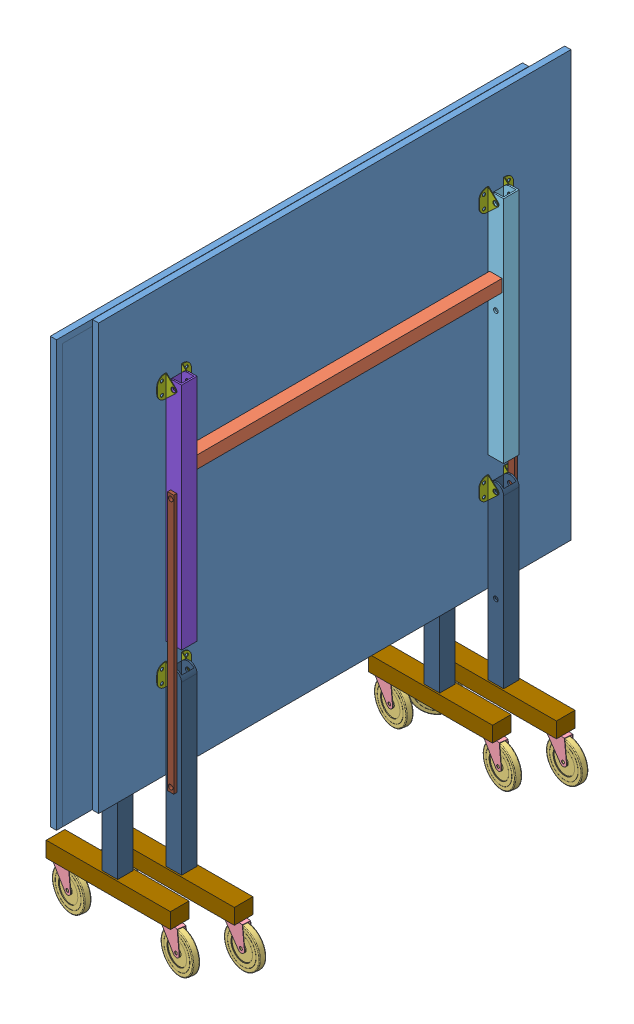
SolidWorks assembly assembly, configuration Default. Lengths in mm.
Overall size (581.84 1820.74 1639.85).
52 component instances, 11 part files, 133 mates.
Components (placement in the parent):
- Copy of tabletop^assembly-1: Copy of tabletop^assembly [Default] at (-385.0848 654.9756 586.0306) x (0 -1 0) z (0.001354 0 0.999999) size (1370 20.1 1525) (virtual)
- leg1-1: leg1 [Default] at (-410.7616 837.4756 86.0649) x (0.999999 0 -0.001354) z (0 -1 0) size (40 1000 40)
- Copy of tabletop^assembly-2: Copy of tabletop^assembly [Default] at (-343.9541 654.9756 471.1751) x (0 -1 0) z (-0.001354 0 -0.999999) size (1370 20.1 1525) (virtual)
- wheel-1: wheel [Default] at (-112.2639 -405.0239 -46.4747) x (-0.080628 0 0.996744) z (-0.996736 -0.004014 -0.080627) size (22.5 125 125)
- wheel support sheet-1: wheel support sheet [Default] at (-155.7324 -312.7529 -50.0409) x (-0.996744 0 -0.080628) z (0.080628 0 -0.996744) size (82.5 81.34 25)
- wheel support sheet-5: wheel support sheet [Default] at (-482.1484 -312.7529 990.8382) x (0.998595 0 -0.052996) z (0.052996 0 0.998595) size (82.5 81.34 25)
- wheel-3: wheel [Default] at (-525.7043 -405.0239 993.0999) x (-0.052996 0 -0.998595) z (0.129125 0.991605 -0.006853) size (22.5 125 125)
- wheel-4: wheel [Default] at (-110.8561 -405.0239 993.5244) x (-0.080628 0 0.996744) z (-0.996683 0.011046 -0.080623) size (22.5 125 125)
- wheel-5: wheel [Default] at (-520.656 -405.0239 -29.1191) x (-0.600076 0 -0.799943) z (0.796376 0.094331 -0.5974) size (22.5 125 125)
- wheel support sheet-6: wheel support sheet [Default] at (-485.7369 -312.7529 -55.2512) x (0.799943 0 -0.600076) z (0.600076 0 0.799943) size (82.5 81.34 25)
- wheel support sheet-7: wheel support sheet [Default] at (-154.3246 -312.7529 989.9582) x (-0.996744 0 -0.080628) z (0.080628 0 -0.996744) size (82.5 81.34 25)
- Copy of leg^assembly-5: Copy of leg^assembly [Default] at (-409.3809 342.4756 1106.064) x (-0.999999 0 0.001354) z (-0.001354 0 -0.999999) size (50 740 50) (virtual)
- Copy of Copy of leg^assembly-6: Copy of Copy of leg^assembly [Default] at (-410.7887 342.4756 66.0649) x (0.999999 0 -0.001354) z (0.001354 0 0.999999) size (50 740 50) (virtual)
- leg hinge-1: leg hinge [Default] at (-384.4147 1040.964 1081.0302) x (-0.001354 0 -0.999999) z (0 1 0) size (30 39.7 70)
- leg hinge-2: leg hinge [Default] at (-385.7548 1073.9872 91.0311) x (0.001354 0 0.999999) z (0 -1 0) size (30 39.7 70)
- leg hinge-3: leg hinge [Default] at (-385.8225 1040.964 41.0311) x (-0.001354 0 -0.999999) z (0 1 0) size (30 39.7 70)
- leg hinge-5: leg hinge [Default] at (-384.3471 1073.9872 1131.0301) x (0.001354 0 0.999999) z (0 -1 0) size (30 39.7 70)
- leg hinge-6: leg hinge [Default] at (-343.2164 1040.964 1016.1746) x (0.001354 0 0.999999) z (0 1 0) size (30 39.7 70)
- leg hinge-7: leg hinge [Default] at (-344.6919 1073.9872 -73.8244) x (-0.001354 0 -0.999999) z (0 -1 0) size (30 39.7 70)
- leg hinge-8: leg hinge [Default] at (-344.6242 1040.964 -23.8245) x (0.001354 0 0.999999) z (0 1 0) size (30 39.7 70)
- leg hinge-9: leg hinge [Default] at (-343.2841 1073.9872 966.1746) x (-0.001354 0 -0.999999) z (0 -1 0) size (30 39.7 70)
- leg1-5: leg1 [Default] at (-319.6309 837.4756 -28.8583) x (0.999999 0 -0.001354) z (0 -1 0) size (40 1000 40)
- Copy of leg^assembly-7: Copy of leg^assembly [Default] at (-319.6578 342.4756 -48.8583) x (0.999999 0 -0.001354) z (0.001354 0 0.999999) size (50 740 50) (virtual)
- Copy (2) of Copy of Copy of leg^assembly-8: Copy (2) of Copy of Copy of leg^assembly [Default] at (-318.25 342.4756 991.1407) x (-0.999999 0 0.001354) z (-0.001354 0 -0.999999) size (50 740 50) (virtual)
- Copy (2) of Copy of leg^assembly-8: Copy (2) of Copy of leg^assembly [Default] at (-118.2503 -311.1814 990.87) x (-0.001354 0 -0.999999) z (0 1 0) size (60 400 50) (virtual)
- Copy (2) of Copy of leg^assembly-9: Copy (2) of Copy of leg^assembly [Default] at (-519.6577 -311.1814 -48.5876) x (0.001354 0 0.999999) z (0 1 0) size (60 400 50) (virtual)
- Copy of Copy of Copy of leg^assembly-9: Copy of Copy of Copy of leg^assembly [Default] at (-318.2501 -291.1814 991.1407) x (0.999999 0 -0.001354) z (0.001354 0 0.999999) size (50 568.66 50) (virtual)
- Copy of Copy of Copy of leg^assembly-11: Copy of Copy of Copy of leg^assembly [Default] at (-319.6579 -291.1814 -48.8583) x (0.999999 0 -0.001354) z (0.001354 0 0.999999) size (50 568.66 50) (virtual)
- leg hinge-11: leg hinge [Default] at (-344.6917 268.9872 -73.8245) x (-0.001354 0 -0.999999) z (0 -1 0) size (30 39.7 70)
- leg hinge-12: leg hinge [Default] at (-343.2839 268.9872 966.1746) x (-0.001354 0 -0.999999) z (0 -1 0) size (30 39.7 70)
- leg hinge-13: leg hinge [Default] at (-343.2162 235.964 1016.1746) x (0.001354 0 0.999999) z (0 1 0) size (30 39.7 70)
- leg hinge-14: leg hinge [Default] at (-344.624 235.964 -23.8245) x (0.001354 0 0.999999) z (0 1 0) size (30 39.7 70)
- bridge-1: bridge [Default] at (-318.3896 354.9756 -73.8601) x (0 1 0) z (-0.999999 0 0.001354) size (835 10 20)
- bridge-2: bridge [Default] at (-316.9006 354.9756 1026.1389) x (0 1 0) z (-0.999999 0 0.001354) size (835 10 20)
- leg hinge-18: leg hinge [Default] at (-384.4147 235.964 1081.0302) x (-0.001354 0 -0.999999) z (0 1 0) size (30 39.7 70)
- leg hinge-19: leg hinge [Default] at (-385.8225 235.964 41.0311) x (-0.001354 0 -0.999999) z (0 1 0) size (30 39.7 70)
- leg hinge-20: leg hinge [Default] at (-385.7548 268.9872 91.0311) x (0.001354 0 0.999999) z (0 -1 0) size (30 39.7 70)
- leg hinge-21: leg hinge [Default] at (-384.3471 268.9872 1131.0301) x (0.001354 0 0.999999) z (0 -1 0) size (30 39.7 70)
- Copy of Copy of Copy of leg^assembly-13: Copy of Copy of Copy of leg^assembly [Default] at (-409.3809 -291.1814 1106.064) x (0.999999 0 -0.001354) z (0.001354 0 0.999999) size (50 568.66 50) (virtual)
- Copy of Copy of Copy of leg^assembly-14: Copy of Copy of Copy of leg^assembly [Default] at (-410.7887 -291.1814 66.0649) x (0.999999 0 -0.001354) z (0.001354 0 0.999999) size (50 568.66 50) (virtual)
- Copy (2) of Copy of leg^assembly-14: Copy (2) of Copy of leg^assembly [Default] at (-609.3807 -311.1814 1106.3347) x (0.001354 0 0.999999) z (0 1 0) size (60 400 50) (virtual)
- Copy (2) of Copy of leg^assembly-15: Copy (2) of Copy of leg^assembly [Default] at (-610.7885 -311.1814 66.3357) x (0.001354 0 0.999999) z (0 1 0) size (60 400 50) (virtual)
- wheel support sheet-10: wheel support sheet [Default] at (-245.3542 -312.7529 1104.059) x (-0.987968 0 -0.154656) z (0.154656 0 -0.987968) size (82.5 81.34 25)
- wheel-9: wheel [Default] at (-202.2721 -405.0239 1110.8535) x (-0.154656 0 0.987968) z (-0.034164 0.999402 -0.005348) size (22.5 125 125)
- wheel support sheet-11: wheel support sheet [Default] at (-595.3538 -312.7529 1104.5328) x (-0.987968 0 -0.154656) z (0.154656 0 -0.987968) size (82.5 81.34 25)
- wheel support sheet-12: wheel support sheet [Default] at (-596.7616 -312.7529 64.5338) x (-0.987968 0 -0.154656) z (0.154656 0 -0.987968) size (82.5 81.34 25)
- wheel support sheet-13: wheel support sheet [Default] at (-246.7589 -312.7529 64.0414) x (-0.987705 0 -0.15633) z (0.15633 0 -0.987705) size (82.5 81.34 25)
- wheel-10: wheel [Default] at (-203.6884 -405.0239 70.9089) x (-0.15633 0 0.987705) z (-0.958469 -0.241504 -0.151702) size (22.5 125 125)
- wheel-11: wheel [Default] at (-553.6795 -405.0239 71.328) x (0.154656 0 -0.987968) z (0.983989 0.089667 0.154033) size (22.5 125 125)
- wheel-12: wheel [Default] at (-552.2717 -405.0239 1111.3271) x (0.154656 0 -0.987968) z (0.237909 -0.970573 0.037242) size (22.5 125 125)
- bridge-3: bridge [Default] at (-409.5338 354.9756 31.0632) x (0 -1 0) z (-0.999999 0 0.001354) size (835 10 20)
- bridge-4: bridge [Default] at (-408.0448 354.9756 1131.0622) x (0 -1 0) z (-0.999999 0 0.001354) size (835 10 20)
Mates (geometry in assembly coordinates):
- Concentric1: concentric anti-aligned: cylinder of wheel-1 through (-111.3568 -405.0239 -57.6882) axis (-0.080628 0 0.996744) radius 5; cylinder of wheel support sheet-1 through (-111.3568 -405.0239 -57.6882) axis (0.080628 0 -0.996744) radius 5
- Coincident4: coincident anti-aligned: plane of wheel-1 through (-111.3568 -405.0239 -57.6882) normal (0.080628 0 -0.996744); plane of wheel support sheet-1 through (-111.3568 -405.0239 -57.6882) normal (-0.080628 0 0.996744)
- Coincident5: coincident anti-aligned: plane of wheel-5 through (-513.905 -405.0239 -20.1196) normal (0.600076 0 0.799943); plane of wheel support sheet-6 through (-513.905 -405.0239 -20.1196) normal (-0.600076 0 -0.799943)
- Concentric2: concentric anti-aligned: cylinder of wheel-5 through (-513.905 -405.0239 -20.1196) axis (-0.600076 0 -0.799943) radius 5; cylinder of wheel support sheet-6 through (-513.905 -405.0239 -20.1196) axis (0.600076 0 0.799943) radius 5
- Coincident7: coincident anti-aligned: circle of wheel support sheet-5; cylinder of wheel-3 through (-525.1081 -405.0239 1004.3342) axis (-0.052996 0 -0.998595) radius 5
- Coincident8: coincident anti-aligned: plane of wheel support sheet-5 through (-526.3005 -405.0239 981.8658) normal (0.052996 0 0.998595); plane of wheel-3 through (-526.3005 -405.0239 981.8658) normal (-0.052996 0 -0.998595)
- Coincident9: coincident anti-aligned: plane of wheel-4 through (-109.949 -405.0239 982.3109) normal (0.080628 0 -0.996744); plane of wheel support sheet-7 through (-109.949 -405.0239 982.3109) normal (-0.080628 0 0.996744)
- Concentric3: concentric aligned: cylinder of wheel-4 through (-109.949 -405.0239 982.3109) axis (-0.080628 0 0.996744) radius 5; cylinder of wheel support sheet-7 through (-111.7632 -405.0239 1004.7376) axis (-0.080628 0 0.996744) radius 5
- Coincident13: coincident aligned: plane of wheel support sheet-5 through (-530.0348 -336.1814 1005.8474) normal (0 1 0); plane of wheel support sheet-7 through (-104.8645 -336.1814 981.4681) normal (0 1 0)
- Coincident20: coincident anti-aligned: plane of leg1-1 through (-1234.4072 52.4756 1087.1807) normal (0 1 0); plane of Copy of Copy of leg^assembly-6 through (-1235.8217 52.4756 42.1807) normal (0 -1 0)
- Coincident21: coincident anti-aligned: plane of leg1-1 through (-1234.4072 52.4756 1087.1807) normal (-0.999999 0 0.001354); plane of Copy of Copy of leg^assembly-6 through (-1235.815 277.4756 47.1817) normal (0.999999 0 -0.001354)
- Coincident22: coincident aligned: plane of leg1-1 through (-1235.7608 12.4756 87.1817) normal (-0.001354 0 -0.999999); plane of Copy of Copy of leg^assembly-6 through (-1235.7608 277.4756 87.1817) normal (-0.001354 0 -0.999999)
- Coincident23: coincident anti-aligned: plane of leg1-1 through (-1194.4072 52.4756 1087.1266) normal (0.999999 0 -0.001354); plane of Copy of leg^assembly-5 through (-1194.3531 277.4756 1127.1266) normal (-0.999999 0 0.001354)
- Coincident24: coincident anti-aligned: plane of leg1-1 through (-1234.4072 12.4756 1087.1807) normal (0 -1 0); plane of Copy of leg^assembly-5 through (-1194.3463 12.4756 1132.1276) normal (0 1 0)
- Coincident25: coincident aligned: plane of leg1-1 through (-1234.4072 12.4756 1087.1807) normal (0.001354 0 0.999999); plane of Copy of leg^assembly-5 through (-1194.4072 277.4756 1087.1266) normal (0.001354 0 0.999999)
- Concentric4: concentric aligned: cylinder of Copy of leg^assembly-5 through (-1214.414 252.4756 1082.1537) axis (0.001354 0 0.999999) radius 7.5; cylinder of leg hinge-1 through (-1214.4167 252.4756 1080.1537) axis (0.001354 0 0.999999) radius 7.5
- Coincident26: coincident anti-aligned: plane of Copy of tabletop^assembly-1; plane of leg hinge-1
- Coincident35: coincident anti-aligned: plane of Copy of tabletop^assembly-1; plane of leg hinge-3
- Coincident36: coincident anti-aligned: plane of Copy of Copy of leg^assembly-6 through (-1240.8217 277.4756 42.1885) normal (-0.001354 0 -0.999999); plane of leg hinge-3 through (-1180.8218 275.4756 42.1072) normal (0.001354 0 0.999999)
- Concentric5: concentric anti-aligned: cylinder of Copy of Copy of leg^assembly-6 through (-1215.7541 252.4756 92.1546) axis (-0.001354 0 -0.999999) radius 7.5; cylinder of leg hinge-3 through (-1215.8245 252.4756 40.1546) axis (0.001354 0 0.999999) radius 7.5
- Coincident37: coincident anti-aligned: plane of Copy of Copy of leg^assembly-6 through (-1240.7541 277.4756 92.1884) normal (0.001354 0 0.999999); plane of leg hinge-2 through (-1250.7541 275.4756 92.202) normal (-0.001354 0 -0.999999)
- Coincident38: coincident anti-aligned: plane of Copy of tabletop^assembly-1; plane of leg hinge-2
- Coincident39: coincident aligned: circle of Copy of Copy of leg^assembly-6; cylinder of leg hinge-2 through (-1215.7514 252.4756 94.1546) axis (-0.001354 0 -0.999999) radius 7.5
- Coincident43: coincident anti-aligned: plane of Copy of leg^assembly-5 through (-1189.414 277.4756 1082.1198) normal (-0.001354 0 -0.999999); plane of leg hinge-1 through (-1179.414 275.4756 1082.1063) normal (0.001354 0 0.999999)
- Coincident44: coincident anti-aligned: plane of Copy of leg^assembly-5 through (-1189.3463 277.4756 1132.1198) normal (0.001354 0 0.999999); plane of leg hinge-5 through (-1249.3463 275.4756 1132.201) normal (-0.001354 0 -0.999999)
- Coincident45: coincident anti-aligned: plane of Copy of tabletop^assembly-1; plane of leg hinge-5
- Concentric6: concentric anti-aligned: cylinder of Copy of leg^assembly-5 through (-1214.414 252.4756 1082.1537) axis (0.001354 0 0.999999) radius 7.5; cylinder of leg hinge-5 through (-1214.3436 252.4756 1134.1536) axis (-0.001354 0 -0.999999) radius 7.5
- Concentric7: concentric anti-aligned: cylinder of Copy of tabletop^assembly-1 through (-1234.326 287.4756 1147.1807) axis (0 -1 0) radius 5; cylinder of leg hinge-5 through (-1234.326 275.4756 1147.1807) axis (0 1 0) radius 5
- Concentric8: concentric anti-aligned: cylinder of Copy of tabletop^assembly-2 through (506.8033 287.4756 1030.0239) axis (0 -1 0) radius 5; cylinder of leg hinge-6 through (506.8033 275.4756 1030.0239) axis (0 1 0) radius 5
- Coincident52: coincident anti-aligned: plane of Copy of tabletop^assembly-2; plane of leg hinge-6
- Concentric9: concentric anti-aligned: cylinder of Copy of tabletop^assembly-2 through (466.8033 287.4756 1030.0781) axis (0 -1 0) radius 5; cylinder of leg hinge-6 through (466.8033 275.4756 1030.0781) axis (0 1 0) radius 5
- Coincident56: coincident aligned: plane of leg hinge-7 through (450.3076 277.4756 -74.9006) normal (0 1 0); plane of leg hinge-8 through (520.3752 277.4756 -24.9954) normal (0 1 0)
- Coincident57: coincident aligned: plane of leg hinge-7 through (450.3076 277.4756 -74.9006) normal (0 1 0); plane of leg hinge-9 through (451.7153 277.4756 965.0985) normal (0 1 0)
- Coincident58: coincident anti-aligned: plane of Copy of tabletop^assembly-2; plane of leg hinge-9
- Concentric10: concentric anti-aligned: cylinder of Copy of tabletop^assembly-2 through (466.695 287.4756 950.0782) axis (0 -1 0) radius 5; cylinder of leg hinge-9 through (466.695 275.4756 950.0782) axis (0 1 0) radius 5
- Concentric11: concentric anti-aligned: cylinder of Copy of tabletop^assembly-2 through (506.695 287.4756 950.024) axis (0 -1 0) radius 5; cylinder of leg hinge-9 through (506.695 275.4756 950.024) axis (0 1 0) radius 5
- Concentric12: concentric anti-aligned: cylinder of Copy of tabletop^assembly-2 through (505.2872 287.4756 -89.975) axis (0 -1 0) radius 5; cylinder of leg hinge-7 through (505.2872 275.4756 -89.975) axis (0 1 0) radius 5
- Concentric13: concentric anti-aligned: cylinder of Copy of tabletop^assembly-2 through (465.2872 287.4756 -89.9209) axis (0 -1 0) radius 5; cylinder of leg hinge-7 through (465.2872 275.4756 -89.9209) axis (0 1 0) radius 5
- Concentric14: concentric anti-aligned: cylinder of Copy of tabletop^assembly-2 through (465.3955 287.4756 -9.921) axis (0 -1 0) radius 5; cylinder of leg hinge-8 through (465.3955 275.4756 -9.921) axis (0 1 0) radius 5
- Coincident60: coincident aligned: cylinder of Copy of tabletop^assembly-2 through (-354.604 1077.4756 -8.811) axis (0.999999 0 -0.001354) radius 5; circle of leg hinge-8
- Coincident61: coincident anti-aligned: plane of leg hinge-8 through (450.3752 275.4756 -24.9006) normal (-0.001354 0 -0.999999); plane of Copy of leg^assembly-7 through (460.3752 277.4756 -24.9142) normal (0.001354 0 0.999999)
- Coincident63: coincident anti-aligned: plane of leg hinge-7 through (520.3075 275.4756 -74.9953) normal (0.001354 0 0.999999); plane of Copy of leg^assembly-7 through (460.3076 277.4756 -74.9141) normal (-0.001354 0 -0.999999)
- Concentric15: concentric aligned: cylinder of leg hinge-8 through (485.3779 252.4756 -22.948) axis (-0.001354 0 -0.999999) radius 7.5; cylinder of Copy of leg^assembly-7 through (485.3752 252.4756 -24.948) axis (-0.001354 0 -0.999999) radius 7.5
- Coincident72: coincident anti-aligned: plane of leg1-5 through (506.7221 52.4756 970.024) normal (0.999999 0 -0.001354); plane of Copy of leg^assembly-7 through (505.3143 277.4756 -69.975) normal (-0.999999 0 0.001354)
- Concentric16: concentric anti-aligned: cylinder of leg hinge-6 through (486.7857 252.4756 1017.051) axis (-0.001354 0 -0.999999) radius 7.5; cylinder of Copy (2) of Copy of Copy of leg^assembly-8 through (486.7153 252.4756 965.0511) axis (0.001354 0 0.999999) radius 7.5
- Coincident73: coincident anti-aligned: plane of leg hinge-6 through (451.783 275.4756 1015.0984) normal (-0.001354 0 -0.999999); plane of Copy (2) of Copy of Copy of leg^assembly-8 through (511.783 277.4756 1015.0172) normal (0.001354 0 0.999999)
- Coincident74: coincident anti-aligned: plane of leg1-5 through (466.7221 52.4756 970.0781) normal (-0.999999 0 0.001354); plane of Copy (2) of Copy of Copy of leg^assembly-8 through (466.7762 277.4756 1010.0781) normal (0.999999 0 -0.001354)
- Coincident75: coincident anti-aligned: plane of leg1-5 through (466.7221 52.4756 970.0781) normal (0 1 0); plane of Copy (2) of Copy of Copy of leg^assembly-8 through (506.783 52.4756 1015.025) normal (0 -1 0)
- Coincident77: coincident aligned: plane of leg1-5 through (465.3685 12.4756 -29.9209) normal (-0.001354 0 -0.999999); plane of Copy of leg^assembly-7 through (465.3685 277.4756 -29.9209) normal (-0.001354 0 -0.999999)
- LimitDistance15: limit distance = 50 mm: line of Copy (2) of Copy of Copy of leg^assembly-8 through (-293.2165 1082.4756 1016.1069) axis (-0.001354 0 -0.999999); plane of Copy of tabletop^assembly-2 through (-344.9863 1339.9756 -291.3243) normal (0.999999 0 -0.001354)
- Concentric17: concentric aligned: cylinder of wheel support sheet-7 through (-143.2503 -336.1814 990.9038) axis (0 -1 0) radius 5; cylinder of Copy (2) of Copy of leg^assembly-8 through (-143.2503 -286.1804 990.9038) axis (0 -1 0) radius 7.5
- Coincident80: coincident anti-aligned: plane of wheel support sheet-7 through (-104.8645 -336.1814 981.4681) normal (0 1 0); plane of Copy (2) of Copy of leg^assembly-8 through (-518.2093 -336.1814 1021.4114) normal (0 -1 0)
- Concentric18: concentric aligned: cylinder of wheel support sheet-5 through (-493.25 -336.1814 991.3776) axis (0 -1 0) radius 5; cylinder of Copy (2) of Copy of leg^assembly-8 through (-493.25 -286.1804 991.3776) axis (0 -1 0) radius 7.5
- Coincident81: coincident anti-aligned: plane of wheel support sheet-6 through (-517.1546 -336.1814 -16.1193) normal (0 1 0); plane of Copy (2) of Copy of leg^assembly-9 through (-119.6987 -336.1814 -79.129) normal (0 -1 0)
- Coincident82: coincident anti-aligned: plane of wheel support sheet-1 through (-106.2723 -336.1814 -58.531) normal (0 1 0); plane of Copy (2) of Copy of leg^assembly-9 through (-119.6987 -336.1814 -79.129) normal (0 -1 0)
- Concentric19: concentric aligned: cylinder of wheel support sheet-6 through (-494.6577 -336.1814 -48.6214) axis (0 -1 0) radius 5; cylinder of Copy (2) of Copy of leg^assembly-9 through (-494.6577 -286.1804 -48.6214) axis (0 -1 0) radius 7.5
- Concentric20: concentric aligned: cylinder of wheel support sheet-1 through (-144.6581 -336.1814 -49.0952) axis (0 -1 0) radius 5; cylinder of Copy (2) of Copy of leg^assembly-9 through (-144.6581 -286.1804 -49.0952) axis (0 -1 0) radius 7.5
- Coincident84: coincident anti-aligned: plane of Copy (2) of Copy of leg^assembly-8 through (-343.2839 -336.1824 966.1746) normal (0.999999 0 -0.001354); plane of Copy of Copy of Copy of leg^assembly-9 through (-343.2839 277.4756 966.1746) normal (-0.999999 0 0.001354)
- Coincident85: coincident aligned: plane of Copy (2) of Copy of leg^assembly-8 through (-518.2161 -291.1814 1016.4114) normal (0 -1 0); plane of Copy of Copy of Copy of leg^assembly-9 through (-293.284 -291.1814 966.1069) normal (0 -1 0)
- Coincident86: coincident anti-aligned: plane of Copy (2) of Copy of leg^assembly-8 through (-518.2838 -331.1814 966.4115) normal (0.001354 0 0.999999); plane of Copy of Copy of Copy of leg^assembly-9 through (-343.2839 277.4756 966.1746) normal (-0.001354 0 -0.999999)
- Coincident87: coincident anti-aligned: plane of Copy (2) of Copy of leg^assembly-9 through (-119.6919 -331.1814 -74.129) normal (0.001354 0 0.999999); plane of Copy of Copy of Copy of leg^assembly-11 through (-344.6917 277.4756 -73.8245) normal (-0.001354 0 -0.999999)
- Coincident88: coincident: line of Copy (2) of Copy of leg^assembly-9 through (-344.6917 -291.1814 -73.8245) axis (0.001354 0 0.999999); plane of Copy of Copy of Copy of leg^assembly-11 through (-344.6917 277.4756 -73.8245) normal (-0.999999 0 0.001354)
- Coincident89: coincident aligned: plane of Copy (2) of Copy of leg^assembly-9 through (-119.6919 -291.1814 -74.129) normal (0 -1 0); plane of Copy of Copy of Copy of leg^assembly-11 through (-294.6918 -291.1814 -73.8921) normal (0 -1 0)
- Concentric22: concentric anti-aligned: cylinder of Copy of tabletop^assembly-2 through (-299.7121 287.4756 -88.8853) axis (0 -1 0) radius 5; cylinder of leg hinge-11 through (-299.7121 275.4756 -88.8853) axis (0 1 0) radius 5
- Concentric23: concentric anti-aligned: cylinder of Copy of tabletop^assembly-2 through (-339.712 287.4756 -88.8312) axis (0 -1 0) radius 5; cylinder of leg hinge-11 through (-339.712 275.4756 -88.8312) axis (0 1 0) radius 5
- Coincident92: coincident anti-aligned: plane of Copy of tabletop^assembly-2; plane of leg hinge-11
- Concentric26: concentric anti-aligned: cylinder of Copy of tabletop^assembly-2 through (-299.6038 287.4756 -8.8854) axis (0 -1 0) radius 5; cylinder of leg hinge-14 through (-299.6038 275.4756 -8.8854) axis (0 1 0) radius 5
- Concentric27: concentric anti-aligned: cylinder of Copy of tabletop^assembly-2 through (-339.6037 287.4756 -8.8313) axis (0 -1 0) radius 5; cylinder of leg hinge-14 through (-339.6037 275.4756 -8.8313) axis (0 1 0) radius 5
- Coincident95: coincident anti-aligned: plane of Copy of tabletop^assembly-2; plane of leg hinge-14
- Coincident96: coincident anti-aligned: plane of Copy of Copy of Copy of leg^assembly-11 through (-344.6917 277.4756 -73.8245) normal (-0.001354 0 -0.999999); plane of leg hinge-11 through (-284.6918 275.4756 -73.9057) normal (0.001354 0 0.999999)
- Concentric28: concentric anti-aligned: cylinder of Copy of Copy of Copy of leg^assembly-11 through (-319.6241 252.4756 -23.8583) axis (-0.001354 0 -0.999999) radius 7.5; cylinder of leg hinge-11 through (-319.6944 252.4756 -75.8583) axis (0.001354 0 0.999999) radius 7.5
- Coincident100: coincident anti-aligned: plane of Copy of tabletop^assembly-2; plane of leg hinge-13
- Coincident101: coincident anti-aligned: plane of Copy of tabletop^assembly-2; plane of leg hinge-12
- Concentric29: concentric anti-aligned: cylinder of Copy of tabletop^assembly-2 through (-338.1959 287.4756 1031.1678) axis (0 -1 0) radius 5; cylinder of leg hinge-13 through (-338.1959 275.4756 1031.1678) axis (0 1 0) radius 5
- Concentric30: concentric anti-aligned: cylinder of Copy of tabletop^assembly-2 through (-298.196 287.4756 1031.1136) axis (0 -1 0) radius 5; cylinder of leg hinge-13 through (-298.196 275.4756 1031.1136) axis (0 1 0) radius 5
- Concentric31: concentric anti-aligned: cylinder of Copy of tabletop^assembly-2 through (-298.3043 287.4756 951.1137) axis (0 -1 0) radius 5; cylinder of leg hinge-12 through (-298.3043 275.4756 951.1137) axis (0 1 0) radius 5
- Concentric32: concentric anti-aligned: cylinder of Copy of tabletop^assembly-2 through (-338.3042 287.4756 951.1678) axis (0 -1 0) radius 5; cylinder of leg hinge-12 through (-338.3042 275.4756 951.1678) axis (0 1 0) radius 5
- Coincident102: coincident anti-aligned: plane of Copy of Copy of Copy of leg^assembly-9 through (-343.2162 277.4756 1016.1746) normal (0.001354 0 0.999999); plane of leg hinge-13 through (-353.2162 275.4756 1016.1881) normal (-0.001354 0 -0.999999)
- Concentric33: concentric aligned: cylinder of Copy of Copy of Copy of leg^assembly-9 through (-318.2163 252.4756 1016.1407) axis (-0.001354 0 -0.999999) radius 7.5; cylinder of leg hinge-13 through (-318.2136 252.4756 1018.1407) axis (-0.001354 0 -0.999999) radius 7.5
- Concentric34: concentric anti-aligned: cylinder of Copy of leg^assembly-7 through (485.3752 -47.5244 -24.948) axis (-0.001354 0 -0.999999) radius 7.5; cylinder of bridge-1 through (485.294 -47.5244 -84.948) axis (0.001354 0 0.999999) radius 7.5
- Coincident104: coincident anti-aligned: plane of Copy of leg^assembly-7 through (460.3076 277.4756 -74.9141) normal (-0.001354 0 -0.999999); plane of bridge-1 through (-334.6917 -37.5244 -73.838) normal (0.001354 0 0.999999)
- Concentric35: concentric anti-aligned: cylinder of Copy of Copy of Copy of leg^assembly-11 through (-319.6241 -47.5244 -23.8583) axis (-0.001354 0 -0.999999) radius 7.5; cylinder of bridge-1 through (-319.7053 -47.5244 -83.8583) axis (0.001354 0 0.999999) radius 7.5
- Coincident105: coincident anti-aligned: plane of Copy (2) of Copy of Copy of leg^assembly-8 through (511.783 277.4756 1015.0172) normal (0.001354 0 0.999999); plane of bridge-2 through (-333.2163 -37.5244 1016.161) normal (-0.001354 0 -0.999999)
- Concentric36: concentric aligned: cylinder of Copy (2) of Copy of Copy of leg^assembly-8 through (486.7153 -47.5244 965.0511) axis (0.001354 0 0.999999) radius 7.5; cylinder of bridge-2 through (486.783 -47.5244 1015.051) axis (0.001354 0 0.999999) radius 7.5
- Concentric37: concentric anti-aligned: cylinder of Copy of Copy of Copy of leg^assembly-9 through (-318.2163 -47.5244 1016.1407) axis (-0.001354 0 -0.999999) radius 7.5; cylinder of bridge-2 through (-318.2163 -47.5244 1016.1407) axis (0.001354 0 0.999999) radius 7.5
- Coincident110: coincident aligned: plane of leg hinge-19 through (-445.8225 277.4756 41.1123) normal (0 1 0); plane of leg hinge-20 through (-375.7549 277.4756 91.0175) normal (0 1 0)
- Coincident111: coincident aligned: plane of leg hinge-18 through (-444.4147 277.4756 1081.1114) normal (0 1 0); plane of leg hinge-20 through (-375.7549 277.4756 91.0175) normal (0 1 0)
- Coincident112: coincident aligned: plane of leg hinge-18 through (-444.4147 277.4756 1081.1114) normal (0 1 0); plane of leg hinge-21 through (-374.3471 277.4756 1131.0166) normal (0 1 0)
- Concentric38: concentric anti-aligned: cylinder of Copy of tabletop^assembly-1 through (-430.7345 287.4756 106.092) axis (0 -1 0) radius 5; cylinder of leg hinge-20 through (-430.7345 275.4756 106.092) axis (0 1 0) radius 5
- Concentric39: concentric anti-aligned: cylinder of Copy of tabletop^assembly-1 through (-390.7345 287.4756 106.0378) axis (0 -1 0) radius 5; cylinder of leg hinge-20 through (-390.7345 275.4756 106.0378) axis (0 1 0) radius 5
- Concentric40: concentric anti-aligned: cylinder of Copy of tabletop^assembly-1 through (-430.8428 287.4756 26.092) axis (0 -1 0) radius 5; cylinder of leg hinge-19 through (-430.8428 275.4756 26.092) axis (0 1 0) radius 5
- Concentric41: concentric anti-aligned: cylinder of Copy of tabletop^assembly-1 through (-390.8428 287.4756 26.0379) axis (0 -1 0) radius 5; cylinder of leg hinge-19 through (-390.8428 275.4756 26.0379) axis (0 1 0) radius 5
- Concentric42: concentric anti-aligned: cylinder of Copy of tabletop^assembly-1 through (-429.3267 287.4756 1146.091) axis (0 -1 0) radius 5; cylinder of leg hinge-21 through (-429.3267 275.4756 1146.091) axis (0 1 0) radius 5
- Concentric43: concentric anti-aligned: cylinder of Copy of tabletop^assembly-1 through (-389.3268 287.4756 1146.0369) axis (0 -1 0) radius 5; cylinder of leg hinge-21 through (-389.3268 275.4756 1146.0369) axis (0 1 0) radius 5
- Concentric44: concentric anti-aligned: cylinder of Copy of tabletop^assembly-1 through (-389.435 287.4756 1066.0369) axis (0 -1 0) radius 5; cylinder of leg hinge-18 through (-389.435 275.4756 1066.0369) axis (0 1 0) radius 5
- Concentric45: concentric anti-aligned: cylinder of Copy of tabletop^assembly-1 through (-429.435 287.4756 1066.0911) axis (0 -1 0) radius 5; cylinder of leg hinge-18 through (-429.435 275.4756 1066.0911) axis (0 1 0) radius 5
- Coincident113: coincident anti-aligned: plane of Copy of tabletop^assembly-1; plane of leg hinge-18
- Coincident115: coincident anti-aligned: plane of leg hinge-18 through (-374.4148 275.4756 1081.0166) normal (0.001354 0 0.999999); plane of Copy of Copy of Copy of leg^assembly-13 through (-434.4147 277.4756 1081.0978) normal (-0.001354 0 -0.999999)
- Concentric46: concentric aligned: cylinder of leg hinge-21 through (-409.3443 252.4756 1133.0639) axis (-0.001354 0 -0.999999) radius 7.5; cylinder of Copy of Copy of Copy of leg^assembly-13 through (-409.347 252.4756 1131.0639) axis (-0.001354 0 -0.999999) radius 7.5
- Coincident116: coincident anti-aligned: plane of leg hinge-20 through (-445.7548 275.4756 91.1123) normal (-0.001354 0 -0.999999); plane of Copy of Copy of Copy of leg^assembly-14 through (-435.7548 277.4756 91.0987) normal (0.001354 0 0.999999)
- Concentric47: concentric aligned: cylinder of leg hinge-20 through (-410.7521 252.4756 93.0649) axis (-0.001354 0 -0.999999) radius 7.5; cylinder of Copy of Copy of Copy of leg^assembly-14 through (-410.7548 252.4756 91.0649) axis (-0.001354 0 -0.999999) radius 7.5
- Coincident119: coincident anti-aligned: plane of Copy of Copy of Copy of leg^assembly-13 through (-434.347 277.4756 1131.0978) normal (0.001354 0 0.999999); plane of Copy (2) of Copy of leg^assembly-14 through (-209.3472 -331.1814 1130.7932) normal (-0.001354 0 -0.999999)
- Coincident120: coincident anti-aligned: plane of Copy of Copy of Copy of leg^assembly-13 through (-384.4147 277.4756 1081.0302) normal (0.999999 0 -0.001354); plane of Copy (2) of Copy of leg^assembly-14 through (-384.3471 -336.1824 1131.0301) normal (-0.999999 0 0.001354)
- Coincident121: coincident anti-aligned: plane of Copy of Copy of Copy of leg^assembly-14 through (-435.8225 277.4756 41.0988) normal (-0.001354 0 -0.999999); plane of Copy (2) of Copy of leg^assembly-15 through (-210.8227 -331.1814 40.7942) normal (0.001354 0 0.999999)
- Coincident122: coincident anti-aligned: plane of Copy of Copy of Copy of leg^assembly-14 through (-435.8225 277.4756 41.0988) normal (-0.999999 0 0.001354); plane of Copy (2) of Copy of leg^assembly-15 through (-435.7548 -336.1824 91.0987) normal (0.999999 0 -0.001354)
- Coincident124: coincident aligned: plane of Copy of Copy of Copy of leg^assembly-14 through (-385.8225 -291.1814 41.0311) normal (0 -1 0); plane of Copy (2) of Copy of leg^assembly-15 through (-210.8227 -291.1814 40.7942) normal (0 -1 0)
- Coincident125: coincident aligned: plane of Copy of Copy of Copy of leg^assembly-13 through (-384.4147 -291.1814 1081.0302) normal (0 -1 0); plane of Copy (2) of Copy of leg^assembly-14 through (-209.4149 -291.1814 1080.7933) normal (0 -1 0)
- Concentric48: concentric aligned: cylinder of Copy (2) of Copy of leg^assembly-14 through (-234.381 -286.1804 1105.8271) axis (0 -1 0) radius 7.5; cylinder of wheel support sheet-10 through (-234.381 -336.1814 1105.8271) axis (0 -1 0) radius 5
- Coincident126: coincident anti-aligned: plane of Copy (2) of Copy of leg^assembly-14 through (-209.4217 -336.1814 1075.7933) normal (0 -1 0); plane of wheel support sheet-10 through (-195.399 -336.1814 1099.2771) normal (0 1 0)
- Concentric49: concentric anti-aligned: cylinder of wheel support sheet-10 through (-200.5322 -405.0239 1099.7388) axis (0.154656 0 -0.987968) radius 5; cylinder of wheel-9 through (-200.5322 -405.0239 1099.7388) axis (-0.154656 0 0.987968) radius 5
- Coincident127: coincident anti-aligned: plane of wheel support sheet-10 through (-200.5322 -405.0239 1099.7388) normal (-0.154656 0 0.987968); plane of wheel-9 through (-200.5322 -405.0239 1099.7388) normal (0.154656 0 -0.987968)
- Coincident128: coincident anti-aligned: plane of Copy (2) of Copy of leg^assembly-14 through (-209.4217 -336.1814 1075.7933) normal (0 -1 0); plane of wheel support sheet-11 through (-545.3987 -336.1814 1099.7509) normal (0 1 0)
- Concentric50: concentric aligned: cylinder of Copy (2) of Copy of leg^assembly-14 through (-584.3807 -286.1804 1106.3009) axis (0 -1 0) radius 7.5; cylinder of wheel support sheet-11 through (-584.3807 -336.1814 1106.3009) axis (0 -1 0) radius 5
- Coincident129: coincident aligned: plane of wheel support sheet-12 through (-546.8065 -336.1814 59.7518) normal (0 1 0); plane of wheel support sheet-13 through (-196.7958 -336.1814 59.3441) normal (0 1 0)
- Coincident130: coincident anti-aligned: plane of Copy (2) of Copy of leg^assembly-15 through (-210.8295 -336.1814 35.7942) normal (0 -1 0); plane of wheel support sheet-13 through (-196.7958 -336.1814 59.3441) normal (0 1 0)
- Concentric51: concentric aligned: cylinder of Copy (2) of Copy of leg^assembly-15 through (-585.7885 -286.1804 66.3018) axis (0 -1 0) radius 7.5; cylinder of wheel support sheet-12 through (-585.7885 -336.1814 66.3018) axis (0 -1 0) radius 5
- Concentric52: concentric aligned: cylinder of Copy (2) of Copy of leg^assembly-15 through (-235.7888 -286.1804 65.828) axis (0 -1 0) radius 7.5; cylinder of wheel support sheet-13 through (-235.7888 -336.1814 65.828) axis (0 -1 0) radius 5
- Concentric53: concentric anti-aligned: cylinder of wheel support sheet-12 through (-555.4194 -405.0239 82.4428) axis (-0.154656 0 0.987968) radius 5; cylinder of wheel-11 through (-555.4194 -405.0239 82.4428) axis (0.154656 0 -0.987968) radius 5
- Coincident131: coincident anti-aligned: plane of wheel support sheet-12 through (-555.4194 -405.0239 82.4428) normal (0.154656 0 -0.987968); plane of wheel-11 through (-555.4194 -405.0239 82.4428) normal (-0.154656 0 0.987968)
- Concentric54: concentric anti-aligned: cylinder of wheel support sheet-13 through (-201.9297 -405.0239 59.7971) axis (0.15633 0 -0.987705) radius 5; cylinder of wheel-10 through (-201.9297 -405.0239 59.7971) axis (-0.15633 0 0.987705) radius 5
- Coincident132: coincident anti-aligned: plane of wheel support sheet-13 through (-205.4471 -405.0239 82.0204) normal (0.15633 0 -0.987705); circle of wheel-10
- Concentric55: concentric aligned: cylinder of wheel support sheet-11 through (-550.5319 -405.0239 1100.2125) axis (0.154656 0 -0.987968) radius 5; cylinder of wheel-12 through (-554.0116 -405.0239 1122.4418) axis (0.154656 0 -0.987968) radius 5
- Coincident133: coincident anti-aligned: plane of wheel support sheet-11 through (-554.0116 -405.0239 1122.4418) normal (0.154656 0 -0.987968); plane of wheel-12 through (-554.0116 -405.0239 1122.4418) normal (-0.154656 0 0.987968)
- Coincident134: coincident anti-aligned: plane of Copy of Copy of leg^assembly-6 through (-1240.8217 277.4756 42.1885) normal (-0.001354 0 -0.999999); plane of bridge-3 through (-1230.8218 -57.5244 42.1749) normal (0.001354 0 0.999999)
- Concentric56: concentric aligned: cylinder of Copy of Copy of leg^assembly-6 through (-1215.7541 -47.5244 92.1546) axis (-0.001354 0 -0.999999) radius 7.5; cylinder of bridge-3 through (-1215.8218 -47.5244 42.1546) axis (-0.001354 0 -0.999999) radius 7.5
- Coincident135: coincident anti-aligned: cylinder of Copy of Copy of Copy of leg^assembly-14 through (-410.7548 -47.5244 91.0649) axis (-0.001354 0 -0.999999) radius 7.5; circle of bridge-3
- Coincident136: coincident anti-aligned: plane of Copy of leg^assembly-5 through (-1189.3463 277.4756 1132.1198) normal (0.001354 0 0.999999); plane of bridge-4 through (-1229.3463 -57.5244 1132.1739) normal (-0.001354 0 -0.999999)
- Concentric57: concentric anti-aligned: cylinder of Copy of leg^assembly-5 through (-1214.414 -47.5244 1082.1537) axis (0.001354 0 0.999999) radius 7.5; cylinder of bridge-4 through (-1214.3328 -47.5244 1142.1536) axis (-0.001354 0 -0.999999) radius 7.5
- Coincident137: coincident aligned: circle of Copy of Copy of Copy of leg^assembly-13; cylinder of bridge-4 through (-409.3335 -47.5244 1141.0639) axis (-0.001354 0 -0.999999) radius 7.5
- Parallel11: parallel aligned: plane of Copy (2) of Copy of leg^assembly-14 through (-209.4217 -336.1814 1075.7933) normal (0 -1 0); plane of Copy (2) of Copy of leg^assembly-15 through (-210.8295 -336.1814 35.7942) normal (0 -1 0)
- LimitDistance19: limit distance = 50 mm: line of Copy of leg^assembly-5 through (-434.4147 1082.4756 1081.0978) axis (0.001354 0 0.999999); plane of Copy of tabletop^assembly-1 through (-384.0527 1339.9756 1348.5299) normal (-0.999999 0 0.001354)
- Parallel13: parallel aligned: plane of Copy (2) of Copy of leg^assembly-8 through (-518.2093 -286.1814 1021.4114) normal (0 1 0); plane of Copy (2) of Copy of leg^assembly-9 through (-119.6987 -286.1814 -79.129) normal (0 1 0)
- Parallel14: parallel aligned: plane of Copy (2) of Copy of leg^assembly-8 through (-518.2093 -286.1814 1021.4114) normal (0 1 0); plane of Copy (2) of Copy of leg^assembly-14 through (-209.4217 -286.1814 1075.7933) normal (0 1 0)
